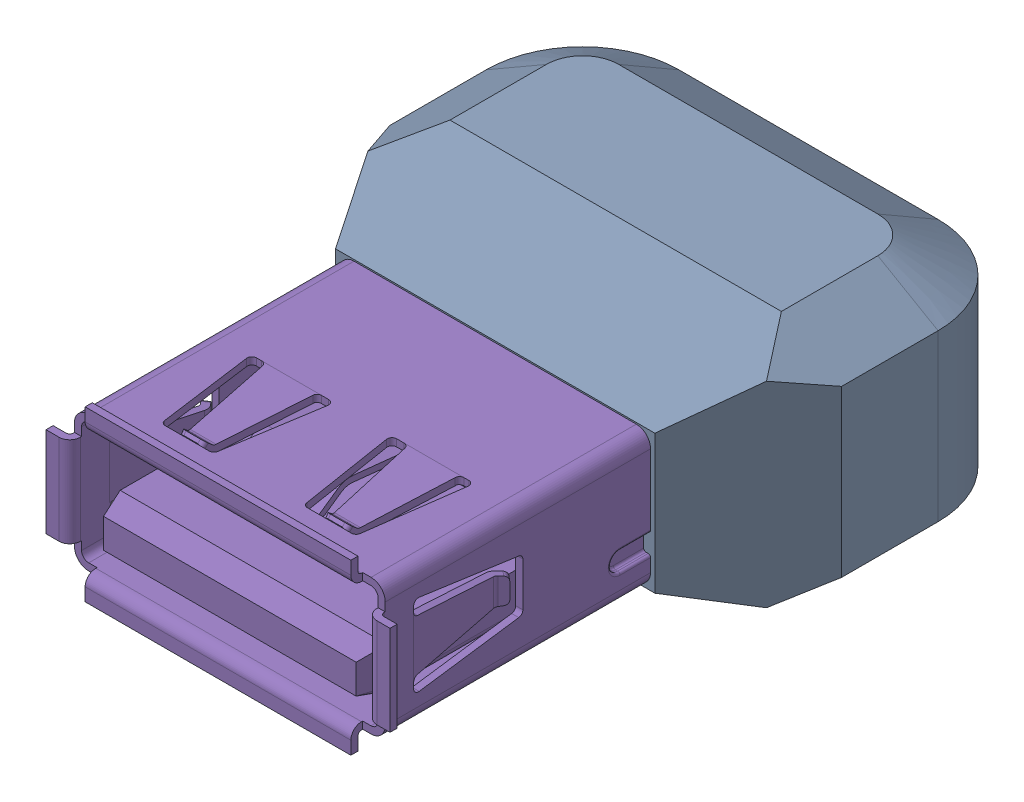
SolidWorks assembly MTN-268, configuration Default. Lengths in mm.
Overall size (19.05 9.91 24.89).
2 component instances, 2 part files, 0 mates.
Components (placement in the parent):
- MTN-268-1: MTN-268 [Default] at origin size (19.05 9.91 13.21)
- 1AA05-008(USB A TYPE FEMALE SOLDER TYPE)-1: 1AA05-008(USB A TYPE FEMALE SOLDER TYPE) [Default] at (0 0 -2.616) x (-1 0 0) z (0 0 1) size (14.5 7.12 17.8)
